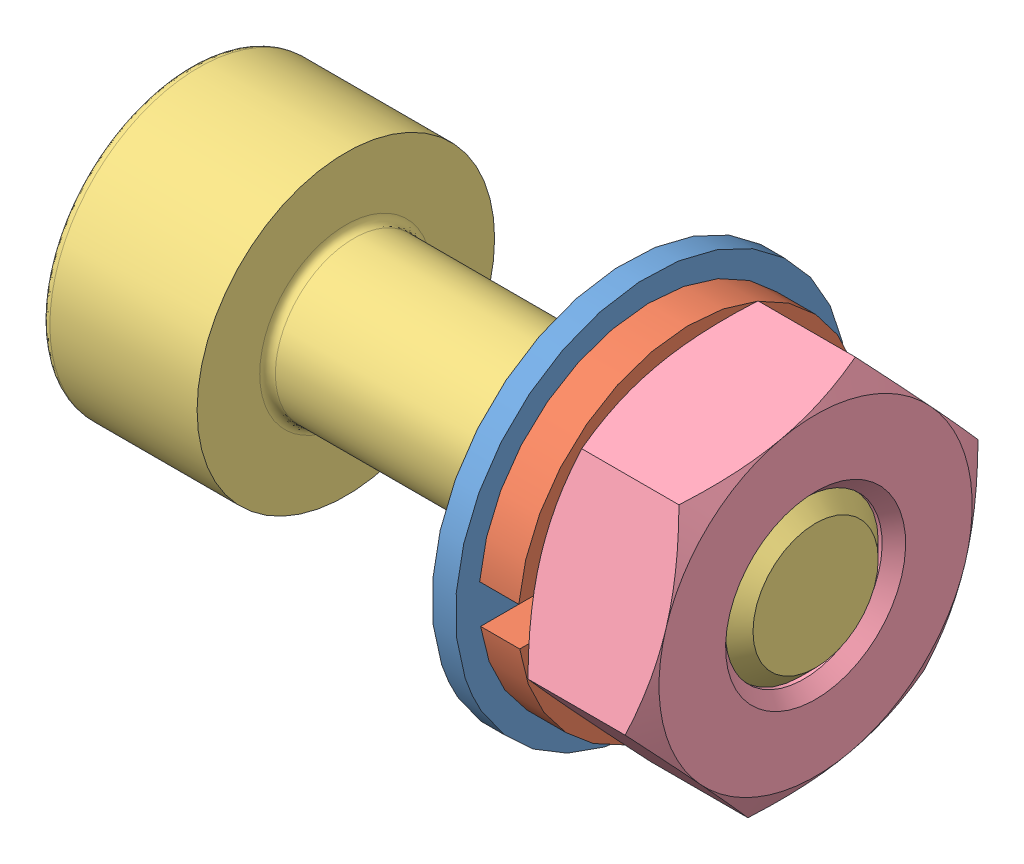
SolidWorks assembly Assem2, configuration Default. Lengths in mm.
Overall size (8 6.6 6.6).
4 component instances, 4 part files, 6 mates.
Components (placement in the parent):
- DIN_125_M2_WASHER_NORMAL-1: DIN_125_M2_WASHER_NORMAL [Default] at (5.9 0 0) x (0 -0.405412 0.914134) z (-1 0 0) size (5 5 0.3)
- DIN_127_M2_SPRING_WASHER-1: DIN_127_M2_SPRING_WASHER [Default] at (6.4 0 0) x (0 0 1) z (-1 0 0) size (4.39 4.4 0.5)
- DIN_912_M2_6H-1: DIN_912_M2_6H [По умолчанию] at origin size (8 3.8 3.8)
- DIN_934_M2_HEX_NUT-1: DIN_934_M2_HEX_NUT [По умолчанию] at (8 0 0) x (0 0.297102 0.954846) z (-1 0 0) size (4 4.62 1.6)
Mates (geometry in assembly coordinates):
- Concentric1: concentric anti-aligned: cylinder of DIN_127_M2_SPRING_WASHER-1 through (10.7615 0 0) axis (1 0 0) radius 1.2; cylinder of DIN_912_M2_6H-1 through (0 0 0) axis (-1 0 0) radius 1
- Concentric2: concentric anti-aligned: cylinder of DIN_125_M2_WASHER_NORMAL-1 through (10.4615 0 0) axis (1 0 0) radius 1.1; cylinder of DIN_912_M2_6H-1 through (0 0 0) axis (-1 0 0) radius 1
- Concentric3: concentric anti-aligned: cylinder of DIN_912_M2_6H-1 through (0 0 0) axis (-1 0 0) radius 1; cylinder of DIN_934_M2_HEX_NUT-1 through (11.2615 0 0) axis (1 0 0) radius 1
- Coincident1: coincident anti-aligned: plane of DIN_127_M2_SPRING_WASHER-1 through (11.2615 0 0) normal (1 0 0); plane of DIN_934_M2_HEX_NUT-1 through (11.2615 0 0) normal (-1 0 0)
- Coincident2: coincident anti-aligned: plane of DIN_125_M2_WASHER_NORMAL-1 through (10.7615 0 0) normal (1 0 0); plane of DIN_127_M2_SPRING_WASHER-1 through (10.7615 0 0) normal (-1 0 0)
- Coincident3: coincident aligned: plane of DIN_912_M2_6H-1 through (8 0 0) normal (1 0 0); plane of DIN_934_M2_HEX_NUT-1 through (8 0 0) normal (1 0 0)
